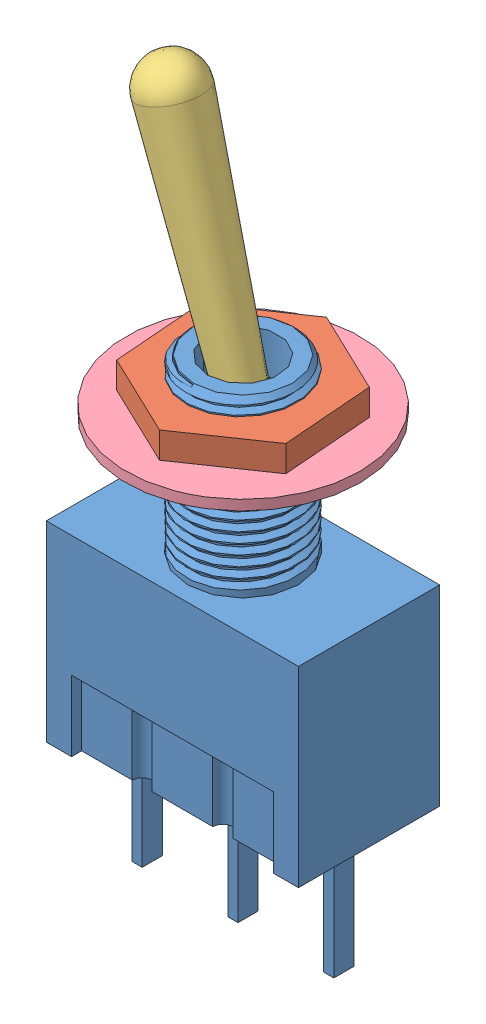
SolidWorks assembly toggle_mts1_assembly, configuration Default. Lengths in mm.
Overall size (15.55 36.55 15.55).
4 component instances, 4 part files, 7 mates.
Components (placement in the parent):
- toggle_mts_1_base_thread-1: toggle_mts_1_base_thread [Default] at origin size (12.5 25.17 7)
- toggle_mts_1_nut-1: toggle_mts_1_nut [Default] at (0 15.8967 -0.4087) x (-0.07757 0 -0.996987) z (0.996987 0 -0.07757) size (9.01 1.63 7.8)
- toggle_mts_1_lever-1: toggle_mts_1_lever [Default] at (0 16.1983 -0.4087) x (0 0 1) z (-0.956305 -0.292372 0) size (3 13.5 3)
- toggle_mts_1_washer-1: toggle_mts_1_washer [Default] at (0 15.3967 -0.4087) x (0.895652 0 -0.444756) z (0.444756 0 0.895652) size (11.6 0.5 11.6)
Mates (geometry in assembly coordinates):
- Screw1: screw = 0.5 aligned: axis of toggle_mts_1_base_thread-1 through (0 17.7 -0.4087) axis (0 -1 0); axis of toggle_mts_1_nut-1 through (0 17.1967 -0.4087) axis (0 -1 0)
- Coincident2: coincident anti-aligned: line of toggle_mts_1_base_thread-1 through (0 16.1983 0) axis (0 0 -1); line of toggle_mts_1_lever-1 through (0 16.1983 -1.4087) axis (0 0 1)
- Coincident3: coincident: axis of toggle_mts_1_lever-1 through (-3.5085 27.6739 -0.4087) axis (0.292372 -0.956305 0); plane of assembly
- LimitAngle2: limit planar angle = 0.296706 rad aligned: axis of toggle_mts_1_lever-1 through (-3.5085 27.6739 -0.4087) axis (0.292372 -0.956305 0); axis of toggle_mts_1_base_thread-1 through (0 17.7 -0.4087) axis (0 -1 0)
- Concentric1: concentric aligned: cylinder of toggle_mts_1_base_thread-1 through (0 18 -0.4087) axis (0 -1 0) radius 2.75; cylinder of toggle_mts_1_washer-1 through (0 15.8967 -0.4087) axis (0 -1 0) radius 2.85
- Coincident6: coincident anti-aligned: plane of toggle_mts_1_nut-1 through (0 15.8967 -0.4087) normal (0 -1 0); plane of toggle_mts_1_washer-1 through (0 15.8967 -0.4087) normal (0 1 0)
- LimitDistance1: limit distance = 5.8967 mm anti-aligned: plane of toggle_mts_1_washer-1 through (0 15.3967 -0.4087) normal (0 -1 0); plane of toggle_mts_1_base_thread-1 through (0 9.5 0) normal (0 1 0)
